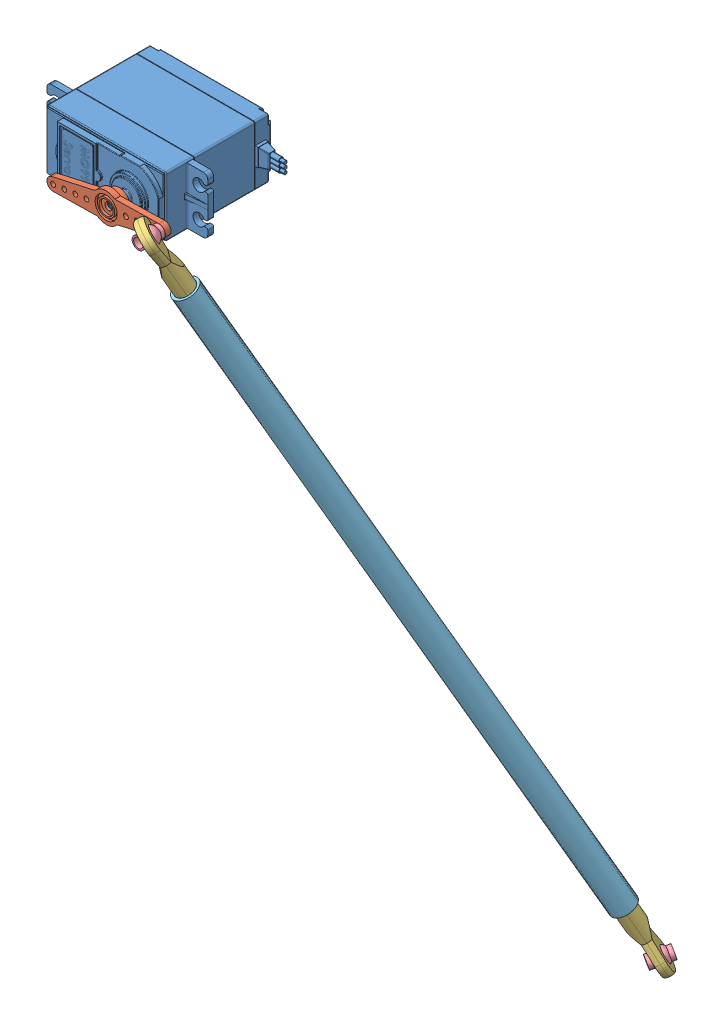
SolidWorks assembly Motor_assem, configuration Default. Lengths in mm.
Overall size (138.99 241.11 125.48).
9 component instances, 5 part files, 14 mates.
Components (placement in the parent):
- MG995-1: MG995 [Default] at origin size (55.5 20 44.5)
- piece de liaison Longue MG996r-1: piece de liaison Longue MG996r [Défaut] at (10 0 44.0793) x (0.993086 0.117391 0) z (0 0 1) size (40 9.79 4.42)
- M3_ball joint-1: M3_ball joint [Default] at (-8.0051 -26.2562 22.5687) x (0.920946 -0.299651 -0.249135) z (0.262378 0.004109 0.964957) size (33.25 24.16 14.74) (flexible)
  - Rótula M3 parte 2-1: Rótula M3 parte 2 [Predeterminado] at (32.9687 17.1233 27.8297) x (-0.509603 -0.666357 0.544309) z (-0.603549 -0.174019 -0.778104) size (7.79 30.01 12.21)
  - Rótula M3 parte 1-2: Rótula M3 parte 1 [Predeterminado] at (17.7293 35.1408 35.6173) x (-0.956256 0.178667 -0.23163) z (0.153318 0.980453 0.123314) size (6 7 6)
- rod-1: rod [Default] at (32.8146 -13.9858 42.3694) x (-0.150945 0.366996 -0.917894) z (0.27358 -0.876758 -0.395538) size (8 8 220)
- M3_ball joint-2: M3_ball joint [Default] at (82.8547 -239.59 -99.9216) x (0.942311 -0.287576 0.171319) z (-0.25582 -0.288605 0.922639) size (33.25 24.16 14.74) (flexible)
  - Rótula M3 parte 2-1: Rótula M3 parte 2 [Predeterminado] at (6.7484 56.8766 40.1408) x (0.229181 0.306692 -0.923805) z (-0.867158 -0.366793 -0.336898) size (7.79 30.01 12.21)
  - Rótula M3 parte 1-2: Rótula M3 parte 1 [Predeterminado] at (17.7293 35.1408 35.6173) x (-0.956256 0.178667 -0.23163) z (0.153318 0.980453 0.123314) size (6 7 6)
Mates (geometry in assembly coordinates):
- Concentric1: concentric aligned: circle of MG995-1; circle of piece de liaison Longue MG996r-1
- Coincident1: coincident anti-aligned: plane of MG995-1 through (10 0 44.5) normal (0 0 1); plane of piece de liaison Longue MG996r-1 through (10 0 44.5) normal (0 0 -1)
- Coincident2: coincident aligned: plane of MG995-1 through (0 0 0) normal (0 0 1)
- Coincident3: coincident aligned: plane of MG995-1 through (0 0 0) normal (0 1 0)
- Coincident4: coincident aligned: plane of MG995-1 through (0 0 0) normal (1 0 0)
- Concentric2: concentric aligned: cylinder of piece de liaison Longue MG996r-1 through (6.9726 17.659 43.3333) axis (0 0 1) radius 0.8333; cylinder of M3_ball joint-1/Rótula M3 parte 1-2 through (6.9726 17.659 53.125) axis (0 0 1) radius 1.55
- Coincident5: coincident anti-aligned: plane of piece de liaison Longue MG996r-1 through (6.9726 17.659 46.125) normal (0 0 1); plane of M3_ball joint-1/Rótula M3 parte 1-2 through (5.5932 18.3659 46.125) normal (0 0 -1)
- Concentric3: concentric anti-aligned: circle of M3_ball joint-1/Rótula M3 parte 2-1; cylinder of rod-1 through (-121.0441 163.0249 176.8745) axis (-0.552286 0.627314 0.549051) radius 3.125
- Coincident6: coincident anti-aligned: plane of M3_ball joint-1/Rótula M3 parte 2-1; plane of rod-1
- Angle2: planar angle = 0.785398 rad aligned: plane of piece de liaison Longue MG996r-1 through (27.7928 2.1033 46.125) normal (0 0 1); plane of M3_ball joint-1/Rótula M3 parte 2-1 through (27.0459 1.3521 50.6472) normal (-0.518497 -0.480792 0.707107)
- LimitAngle2: limit planar angle = 0.169784 rad anti-aligned: plane of piece de liaison Longue MG996r-1 through (10 0 44.0793) normal (-0.117391 0.993086 0); plane of MG995-1 through (20 10 36) normal (1 0 0)
- Concentric4: concentric aligned: cylinder of rod-1 through (-121.0441 163.0249 176.8745) axis (-0.552286 0.627314 0.549051) radius 3.125; circle of M3_ball joint-2/Rótula M3 parte 2-1
- Coincident7: coincident anti-aligned: plane of rod-1; plane of M3_ball joint-2/Rótula M3 parte 2-1
- Parallel2: parallel aligned: plane of M3_ball joint-1/Rótula M3 parte 2-1 through (8.0152 17.619 50.6438) normal (0.707097 0.003638 0.707107); plane of M3_ball joint-2/Rótula M3 parte 2-1 through (-133.7014 178.5876 191.5304) normal (0.707097 0.003638 0.707107)
